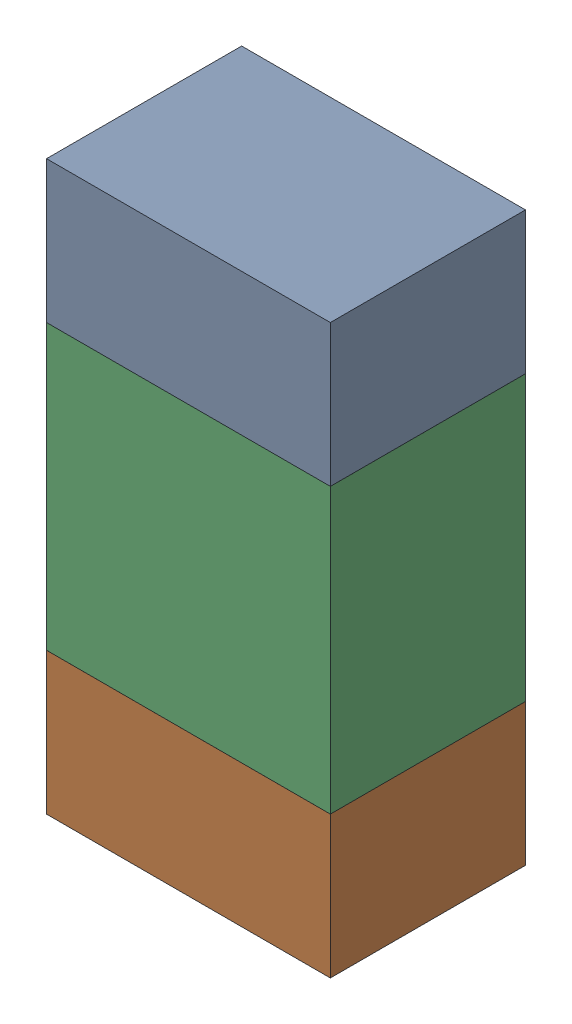
SolidWorks assembly R13, configuration ﾃﾞﾌｫﾙﾄ. Lengths in mm.
Overall size (0.8 1.6 0.55).
6 component instances, 2 part files, 0 mates.
Components (placement in the parent):
- 689261784-1: 689261784 [ﾃﾞﾌｫﾙﾄ] at (71.5001 48.8499 0) size (0.8 0.4 0.55)
  - Extruded_34-1: Extruded_34 [ﾃﾞﾌｫﾙﾄ] at origin size (0.8 0.4 0.55)
- 689261784-2: 689261784 [ﾃﾞﾌｫﾙﾄ] at (71.5001 47.6499 0) size (0.8 0.4 0.55)
  - Extruded_34-1: Extruded_34 [ﾃﾞﾌｫﾙﾄ] at origin size (0.8 0.4 0.55)
- 689261648-1: 689261648 [ﾃﾞﾌｫﾙﾄ] at (71.5001 48.25 0) size (0.8 0.8 0.55)
  - Extruded_33-1: Extruded_33 [ﾃﾞﾌｫﾙﾄ] at origin size (0.8 0.8 0.55)
